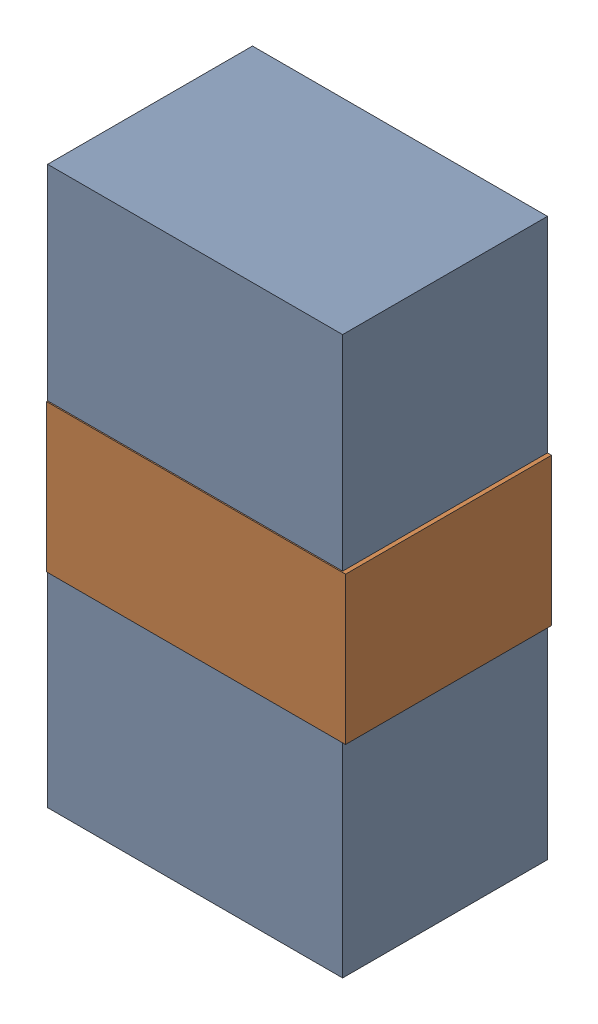
SolidWorks assembly LED2_Motor_4Kanaloa_v2.0.0_Motor, configuration Default. Lengths in mm.
Overall size (1.83 3.4 1.26).
4 component instances, 2 part files, 0 mates.
Components (placement in the parent):
- 334788016-1: 334788016 [Default] at (85.3905 90.678 0) size (1.8 3.4 1.25)
  - Extruded_12-1: Extruded_12 [Default] at origin size (1.8 3.4 1.25)
- 334787760-1: 334787760 [Default] at (85.403 90.678 0) size (1.83 0.9 1.26)
  - Extruded_13-1: Extruded_13 [Default] at origin size (1.83 0.9 1.26)
